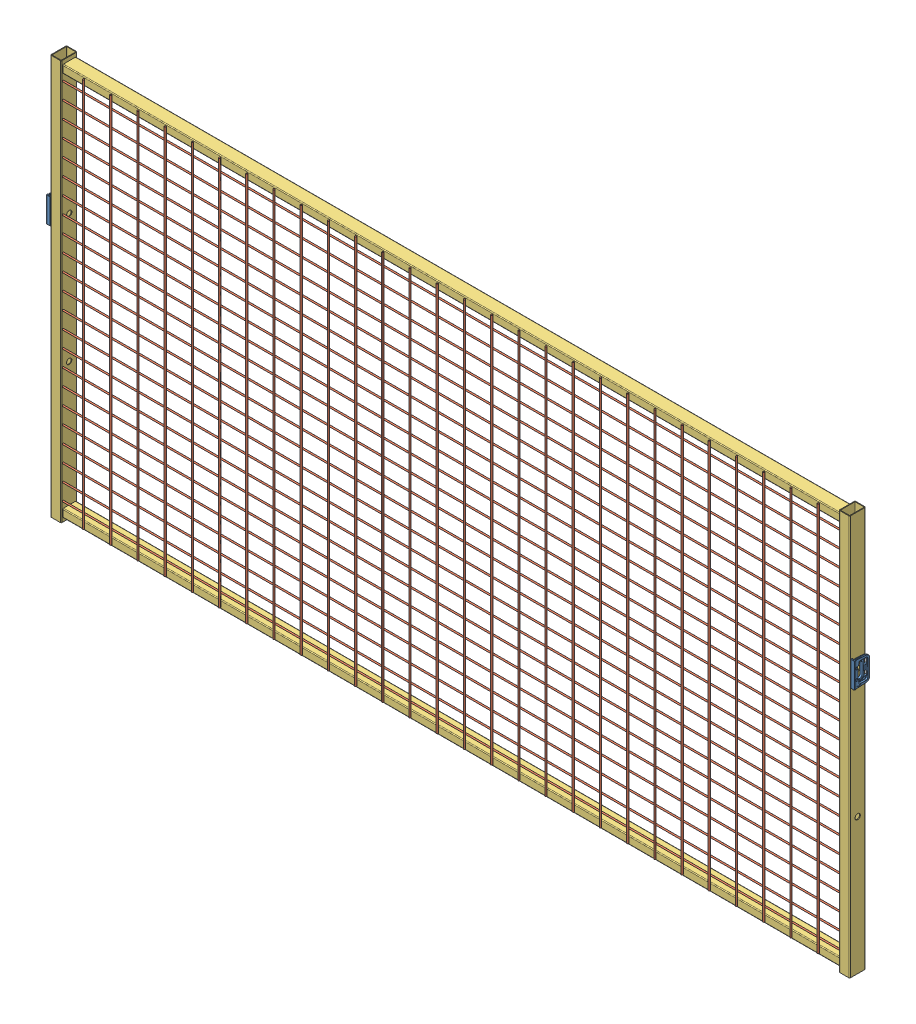
SolidWorks assembly W322-075150-Axelent, configuration Default. Lengths in mm.
Overall size (1515.63 750 30).
4 component instances, 3 part files, 0 mates.
Components (placement in the parent):
- G2032-1: G2032 [Default] at (-749 120 0) size (9.31 48.01 29.42)
- G2032-2: G2032 [Default] at (749 120 0) x (-1 0 0) z (0 0 1) size (9.31 48.01 29.42)
- NÄT-50x30_III_N-05030-075-150-1: NÄT-50x30_III_N-05030-075-150 [Default] at (0 0 13.5) x (-1 0 0) z (0 0 -1) size (1472 730 4.75)
- RAM-30_RAM-075-150-1: RAM-30_RAM-075-150 [Default] at origin size (1498 750 30)
